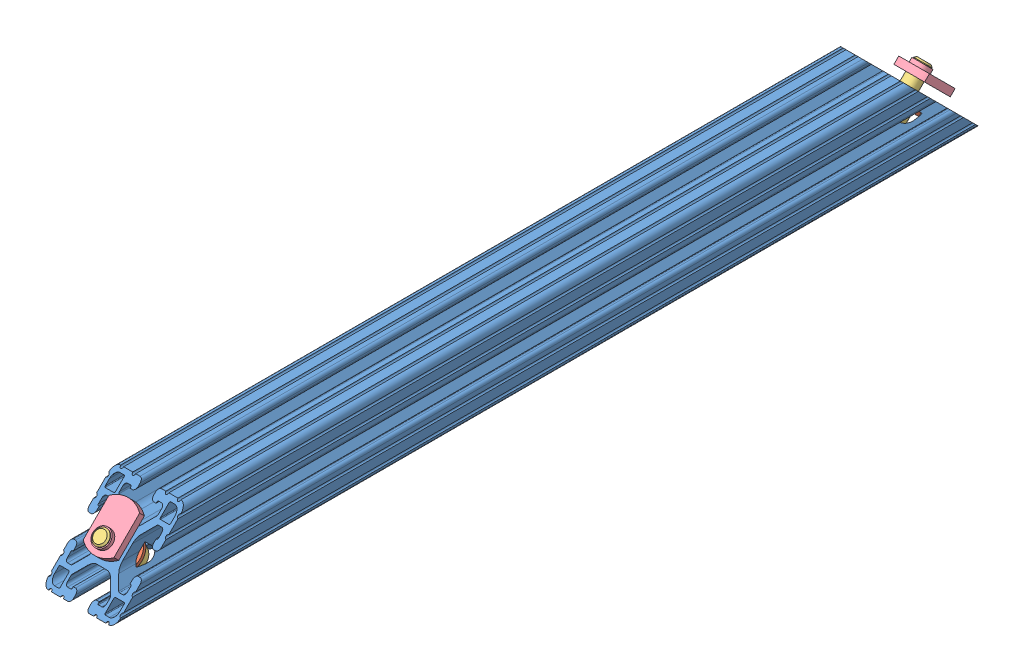
SolidWorks assembly 8020-2563-$PARTNUMBER, configuration Default. Lengths in mm.
Overall size (38.1 42.71 458.57).
9 component instances, 4 part files, 4 mates.
Components (placement in the parent):
- 8020-2563-$PARTNUMBER_2563-1: 8020-2563-$PARTNUMBER_2563 [Default] at (-62.7169 -30.0123 282.2835) size (38.1 38.69 457.2)
- 8020-2563-$PARTNUMBER_15sHW-1: 8020-2563-$PARTNUMBER_15sHW [Default] at (-61.3052 -38.3993 257.6253) x (1 0 0) z (0 0.707107 -0.707107) size (17.58 26.99 26.64)
  - 8020-2563-$PARTNUMBER_3260-1: 8020-2563-$PARTNUMBER_3260 [Default] at (-1.4117 -2.7079 1.9649) size (17.58 1.68 17.58)
  - 8020-2563-$PARTNUMBER_3112-1: 8020-2563-$PARTNUMBER_3112 [3112] at (-1.4117 6.0678 1.9649) x (0 -1 0) z (0 0 1) size (26.99 11.91 11.91)
  - 8020-2563-$PARTNUMBER_3278-1: 8020-2563-$PARTNUMBER_3278 [Default] at (-1.4117 -15.8905 7.3243) x (0 0 1) z (0 -1 0) size (24.99 16.21 5.64)
- 8020-2563-$PARTNUMBER_15sHW-2: 8020-2563-$PARTNUMBER_15sHW [Default] at (-61.3052 -35.6206 -147.4795) x (1 0 0) z (0 -0.707107 -0.707107) size (17.58 26.99 26.64)
  - 8020-2563-$PARTNUMBER_3260-1: 8020-2563-$PARTNUMBER_3260 [Default] at (-1.4117 -2.7079 1.9649) size (17.58 1.68 17.58)
  - 8020-2563-$PARTNUMBER_3112-1: 8020-2563-$PARTNUMBER_3112 [3112] at (-1.4117 6.0678 1.9649) x (0 -1 0) z (0 0 1) size (26.99 11.91 11.91)
  - 8020-2563-$PARTNUMBER_3278-1: 8020-2563-$PARTNUMBER_3278 [Default] at (-1.4117 -15.8905 7.3243) x (0 0 1) z (0 -1 0) size (24.99 16.21 5.64)
Mates (geometry in assembly coordinates):
- Concentric11: concentric anti-aligned: cylinder of 8020-2563-$PARTNUMBER_2563-1 through (-62.7169 -22.6485 270.5973) axis (0 -0.707107 -0.707107) radius 4.1656; cylinder of 8020-2563-$PARTNUMBER_15sHW-1/8020-2563-$PARTNUMBER_3260-1 through (-62.7169 -35.6879 257.558) axis (0 0.707107 0.707107) radius 4.4323
- Coincident11: coincident anti-aligned: plane of 8020-2563-$PARTNUMBER_2563-1 through (-62.7169 -34.5025 258.7434) normal (0 -0.707107 -0.707107); plane of 8020-2563-$PARTNUMBER_15sHW-1/8020-2563-$PARTNUMBER_3260-1 through (-62.7169 -34.5025 258.7434) normal (0 0.707107 0.707107)
- Concentric21: concentric anti-aligned: cylinder of 8020-2563-$PARTNUMBER_2563-1 through (-62.7169 -22.6485 -163.2303) axis (0 -0.707107 0.707107) radius 4.1656; cylinder of 8020-2563-$PARTNUMBER_15sHW-2/8020-2563-$PARTNUMBER_3260-1 through (-62.7169 -35.6879 -150.191) axis (0 0.707107 -0.707107) radius 4.4323
- Coincident21: coincident anti-aligned: plane of 8020-2563-$PARTNUMBER_2563-1 through (-62.7169 -34.5025 -151.3763) normal (0 -0.707107 0.707107); plane of 8020-2563-$PARTNUMBER_15sHW-2/8020-2563-$PARTNUMBER_3260-1 through (-62.7169 -34.5025 -151.3763) normal (0 0.707107 -0.707107)
